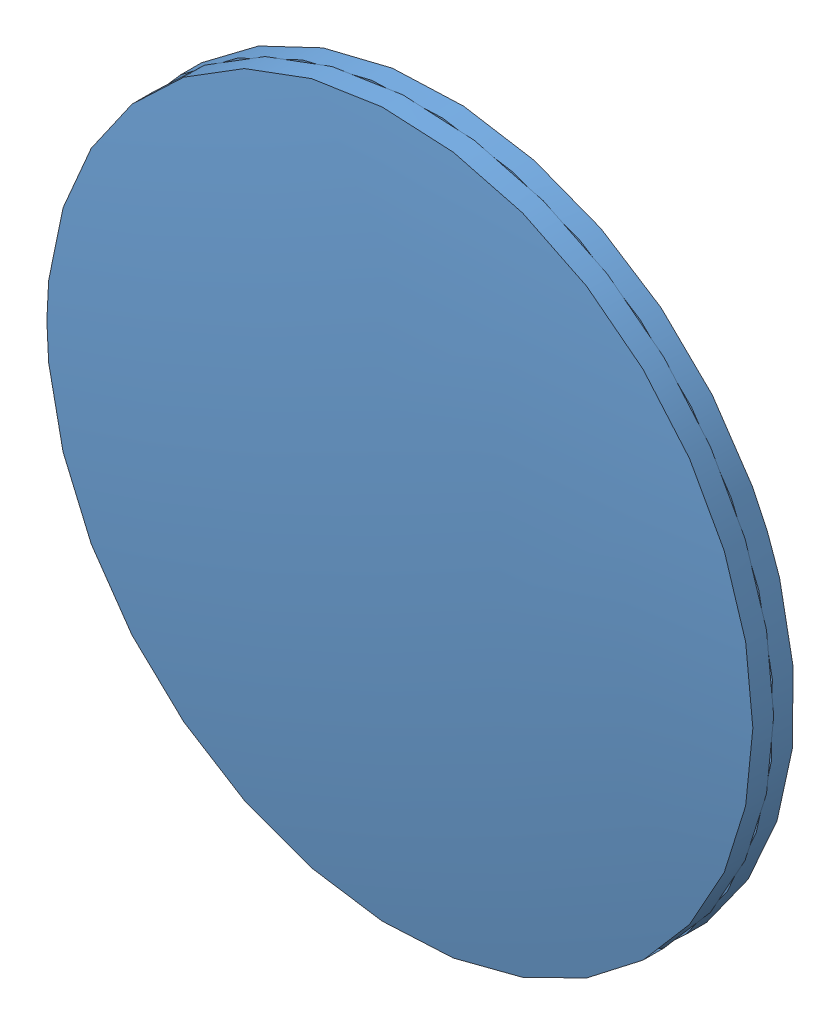
SolidWorks assembly 200 mm lens, configuration Default. Lengths in mm.
Overall size (66.38 66.38 6.55).
2 component instances, 1 part files, 1 mates.
Components (placement in the parent):
- 200 mm lens half-1: 200 mm lens half [Default] at (89.9388 90.4266 -92.3673) size (50.8 50.8 3.28)
- 200 mm lens half-2: 200 mm lens half [Default] at (89.9388 90.4266 266.2247) x (-0.923728 -0.383049 0) z (0 0 -1) size (50.8 50.8 3.28)
Mates (geometry in assembly coordinates):
- Coincident1: coincident anti-aligned: circle of 200 mm lens half-1; circle of 200 mm lens half-2
